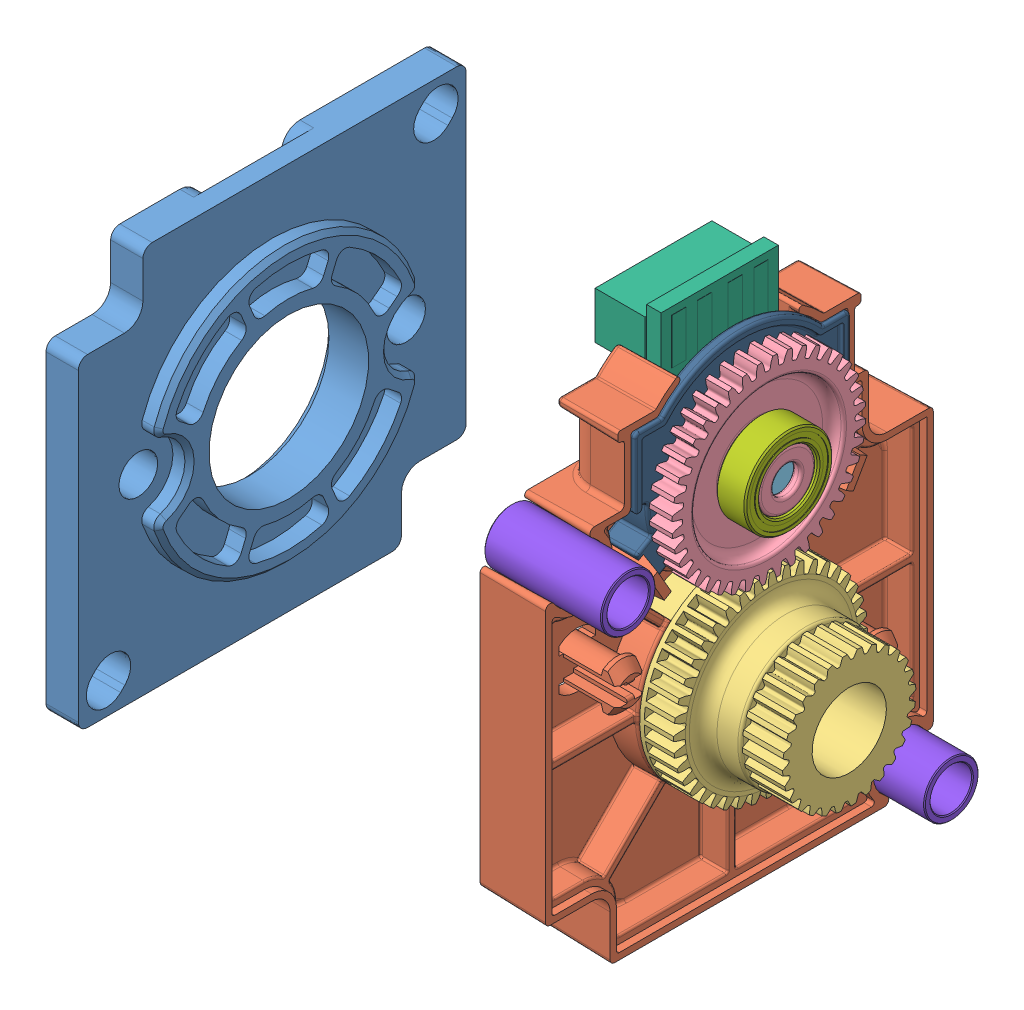
SolidWorks assembly VersaPlanetary_v2_Single_Stage_10_1_with_775_SeriesELEVATOR, configuration Default. Lengths in mm.
Overall size (66 58.21 43.13).
19 component instances, 16 part files, 18 mates.
Components (placement in the parent):
- 217-2625-026 Rev1-1: 217-2625-026 Rev1 [Default] at (93.7544 -5.667 -47.5304) x (0 -1 0) z (-1 0 0) (suppressed, hidden)
- 217-2625-003 Rev1-1: 217-2625-003 Rev1 [Default] at (109.127 -5.667 -47.5304) x (0 -1 0) z (1 0 0) (suppressed, hidden)
- 217-2625-025 Rev1-1: 217-2625-025 Rev1 [Default] at (51.6544 -5.667 -47.5304) x (0 -1 0) z (-1 0 0) (suppressed, hidden)
- 217-2822-002 Rev4-1: 217-2822-002 Rev4 [Default] at (42.4044 -5.667 -47.5304) x (0 -1 0) z (-1 0 0) size (42 42 5.3)
- 217-4347-000 Rev1-1: 217-4347-000 Rev1 [Default] at (40.6544 -5.667 -47.5304) x (-1 0 0) z (0 1 0) (suppressed, hidden)
- 217-2816-001 Rev1-1: 217-2816-001 Rev1 [Default] at (68.5044 -5.667 -47.5304) x (0 -1 0) z (1 0 0) (suppressed, hidden)
- 217-2816-001 Rev1-2: 217-2816-001 Rev1 [Default] at (81.2044 -5.667 -47.5304) x (0 -1 0) z (1 0 0) (suppressed, hidden)
- VersaPlanetary_Integrated_Encoder_217-5046ELEVATOR-1: VersaPlanetary_Integrated_Encoder_217-5046ELEVATOR [Default] at (94.7544 -5.667 -47.5304) x (0 -1 0) z (1 0 0) size (58.21 43.13 22.65)
  - 217-4783-001 Rev3-1: 217-4783-001 Rev3 [Default] at (0 0 2.75) (suppressed, hidden)
  - 217-4783-002 Rev7_Sealed Config-1: 217-4783-002 Rev7_Sealed Config [Default] at (0 0 -7.2) x (0 1 0) z (0 0 1) size (42 51.56 9.32)
  - 217-4783-005 Rev7_40t_spur_REF_14deg-1: 217-4783-005 Rev7_40t_spur_REF_14deg [Default] at (0 0 5.95) x (0.660339 0.750968 0) z (0 0 1) size (21.16 21.1 17.1)
  - 217-4783-004 Rev2_40t_spur_REF_14deg-1: 217-4783-004 Rev2_40t_spur_REF_14deg [Default] at (-20.05 0 5.2) x (-0.718289 0.695745 0) z (0 0 1) size (21.07 21.07 4.88)
  - 217-4783-008 Rev2-1: 217-4783-008 Rev2 [Default] at (-20.05 0 2.2) x (0.307149 -0.951661 0) z (0.951661 0.307149 0) size (5 4 5)
  - PCBA Rev3-1: PCBA Rev3 [Default] at (-20.05 0 -2.1252) x (0 1 0) z (-1 0 0) size (15.93 10.15 24.58)
  - 217-2788-001 Rev3_57155K375-1: 217-2788-001 Rev3_57155K375 [Default] at (-20.05 0 3.8125) x (-0.99574 0.092202 0) z (0 0 1) size (9.53 9.53 3.17)
  - 217-4783-006 Rev3-1: 217-4783-006 Rev3 [Default] at (17.5 17.5 -0.85) x (-0.867641 0.497191 0) z (0 0 1) size (5.9 5.9 12.7)
  - 217-4783-006 Rev3-2: 217-4783-006 Rev3 [Default] at (-17.5 -17.5 -0.85) x (0.825154 -0.564908 0) z (0 0 1) size (5.9 5.9 12.7)
  - 217-4783-007 Rev1-1: 217-4783-007 Rev1 [Default] at (-16.45 0 -5.2) x (0 1 0) z (0 0 1) size (6 10.71 3.56)
  - 217-4783-003 Rev4-1: 217-4783-003 Rev4 [Default] at (-20.05 0 -1.02) x (0 1 0) z (0 0 1) size (23.4 21.71 4.21)
Mates (geometry in assembly coordinates):
- Coincident1: coincident anti-aligned: plane of 217-2625-026 Rev1-1 through (116.8794 16.558 -25.3054) normal (1 0 0); plane of 217-2625-003 Rev1-1 through (116.8794 -5.667 -47.5304) normal (-1 0 0)
- Concentric1: concentric anti-aligned: cylinder of 217-2625-026 Rev1-1 through (116.8794 -5.667 -47.5304) axis (-1 0 0) radius 13.995; cylinder of 217-2625-003 Rev1-1 through (116.8794 -5.667 -47.5304) axis (1 0 0) radius 8.5
- Concentric2: concentric aligned: cylinder of 217-2822-002 Rev4-1 through (40.6544 -5.667 -47.5304) axis (1 0 0) radius 8.65; cylinder of 217-4347-000 Rev1-1 through (40.6544 -5.667 -47.5304) axis (1 0 0) radius 8.9
- Concentric3: concentric aligned: cylinder of 217-2822-002 Rev4-1 through (40.6544 -5.667 -33.0304) axis (1 0 0) radius 2.1; cylinder of 217-4347-000 Rev1-1 through (40.6544 -5.667 -33.0304) axis (1 0 0) radius 1.65
- Concentric4: concentric aligned: cylinder of 217-2822-002 Rev4-1 through (40.6544 -5.667 -62.0304) axis (1 0 0) radius 2.1; cylinder of 217-4347-000 Rev1-1 through (40.6544 -5.667 -62.0304) axis (1 0 0) radius 1.65
- Coincident2: coincident anti-aligned: plane of 217-2822-002 Rev4-1 through (40.6544 -5.667 -47.5304) normal (-1 0 0); plane of 217-4347-000 Rev1-1 through (40.6544 -5.667 -38.6304) normal (1 0 0)
- Concentric8: concentric aligned: cylinder of 217-2625-025 Rev1-1 through (58.6544 -5.667 -47.5304) axis (1 0 0) radius 10.5; cylinder of 217-4347-000 Rev1-1 through (40.6544 -5.667 -47.5304) axis (1 0 0) radius 2.5
- Coincident5: coincident aligned: plane of 217-2625-025 Rev1-1 through (62.1544 15.333 -26.5304) normal (0 0 1); plane of 217-2822-002 Rev4-1 through (40.6544 -5.667 -26.5304) normal (0 0 1)
- Coincident6: coincident anti-aligned: plane of 217-2625-025 Rev1-1 through (44.1544 -27.892 -25.3054) normal (-1 0 0); plane of 217-2822-002 Rev4-1 through (44.1544 -5.667 -47.5304) normal (1 0 0)
- Concentric9: concentric aligned: cylinder of 217-2625-025 Rev1-1 through (58.6544 -5.667 -47.5304) axis (1 0 0) radius 10.5; cylinder of 217-2816-001 Rev1-1 through (62.6044 -5.667 -47.5304) axis (1 0 0) radius 20
- Coincident7: coincident anti-aligned: plane of 217-2625-025 Rev1-1 through (62.1544 16.558 -25.3054) normal (1 0 0); plane of 217-2816-001 Rev1-1 through (62.1544 -26.667 -68.5304) normal (-1 0 0)
- Concentric10: concentric aligned: cylinder of 217-2625-025 Rev1-1 through (58.6544 -5.667 -47.5304) axis (1 0 0) radius 10.5; cylinder of 217-2816-001 Rev1-2 through (75.3044 -5.667 -47.5304) axis (1 0 0) radius 20
- Coincident8: coincident anti-aligned: plane of 217-2816-001 Rev1-1 through (74.8544 -26.667 -68.5304) normal (1 0 0); plane of 217-2816-001 Rev1-2 through (74.8544 -26.667 -68.5304) normal (-1 0 0)
- Concentric11: concentric anti-aligned: cylinder of 217-2816-001 Rev1-2 through (87.5554 -5.667 -47.5304) axis (-1 0 0) radius 19; cylinder of VersaPlanetary_Integrated_Encoder_217-5046ELEVATOR-1/217-4783-005 Rev7_40t_spur_REF_14deg-1 through (130.7303 -5.667 -47.5304) axis (1 0 0) radius 7.42
- Coincident9: coincident anti-aligned: plane of 217-2816-001 Rev1-2 through (87.5544 -26.667 -68.5304) normal (1 0 0); plane of VersaPlanetary_Integrated_Encoder_217-5046ELEVATOR-1/217-4783-002 Rev7_Sealed Config-1 through (87.5544 -5.667 -47.5304) normal (-1 0 0)
- Concentric12: concentric aligned: cylinder of 217-2625-026 Rev1-1 through (116.8794 -5.667 -47.5304) axis (-1 0 0) radius 13.995; cylinder of VersaPlanetary_Integrated_Encoder_217-5046ELEVATOR-1/217-4783-001 Rev3-1 through (101.7544 -5.667 -47.5304) axis (-1 0 0) radius 20.025
- Coincident10: coincident anti-aligned: plane of 217-2625-026 Rev1-1 through (100.2544 -5.667 -47.5304) normal (-1 0 0); plane of VersaPlanetary_Integrated_Encoder_217-5046ELEVATOR-1/217-4783-001 Rev3-1 through (100.2544 -5.667 -47.5304) normal (1 0 0)
- Concentric13: concentric aligned: cylinder of 217-2816-001 Rev1-2 through (87.5544 11.833 -30.0304) axis (1 0 0) radius 2.1526; cylinder of VersaPlanetary_Integrated_Encoder_217-5046ELEVATOR-1/217-4783-006 Rev3-2 through (101.2805 11.833 -30.0304) axis (1 0 0) radius 2.2479
